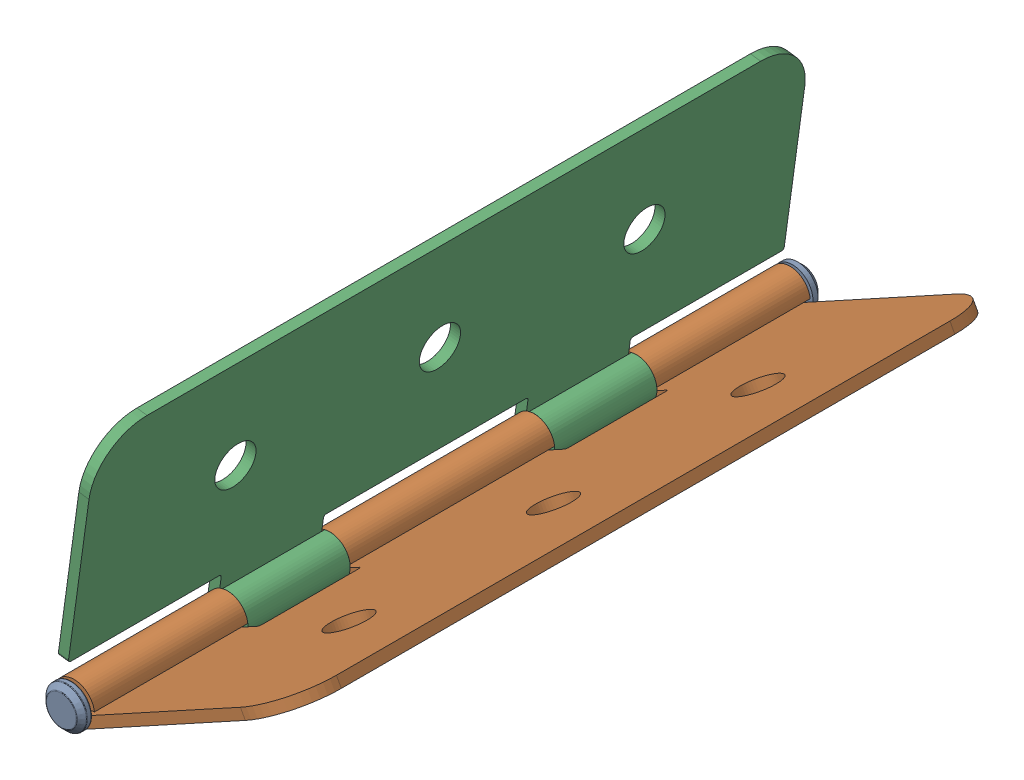
SolidWorks assembly Hinge Assembly, configuration Default. Lengths in mm.
Overall size (119.23 128.87 362.5).
3 component instances, 3 part files, 4 mates.
Components (placement in the parent):
- Pin for Door-1: Pin for Door [Default] at origin size (20 20 362.5)
- Door Hinge-1: Door Hinge [Default] at (55.6601 24.1734 35.0125) x (0 0 -1) z (-0.480619 0.87693 0) size (350 125 20)
- Door Hinge Part 2-1: Door Hinge Part 2 [Default] at (2.9683 68.0626 -34.9875) x (0 0 1) z (0.990734 -0.135813 0) size (350 125 20)
Mates (geometry in assembly coordinates):
- Concentric2: concentric anti-aligned: cylinder of Pin for Door-1 through (0 0 176.2625) axis (0 0 -1) radius 4.625; cylinder of Door Hinge-1 through (0 0 50.0125) axis (0 0 1) radius 5
- Width1: width aligned: plane of Pin for Door-1 through (0 0 176.2625) normal (0 0 -1); plane of Pin for Door-1 through (0 0 -176.2375) normal (0 0 1); plane of Door Hinge-1 through (-3.9631 -13.5755 -174.9875) normal (0 0 -1); plane of Door Hinge-1 through (105.6531 46.5019 175.0125) normal (0 0 1)
- Hinge1: hinge anti-aligned: cylinder of Door Hinge Part 2-1 through (0 0 50.0125) axis (0 0 -1) radius 5; cylinder of Door Hinge-1 through (0 0 50.0125) axis (0 0 1) radius 5; plane of Door Hinge Part 2-1 through (0 0 -99.9875) normal (0 0 -1); plane of Door Hinge-1 through (0 0 -99.9875) normal (0 0 1)
- LimitAngle2: limit planar angle = 0.933202 rad anti-aligned: plane of Door Hinge Part 2-1 through (10.6649 114.6135 -174.9875) normal (0.990734 -0.135813 0); plane of Door Hinge-1 through (103.25 50.8865 175.0125) normal (-0.480619 0.87693 0)
